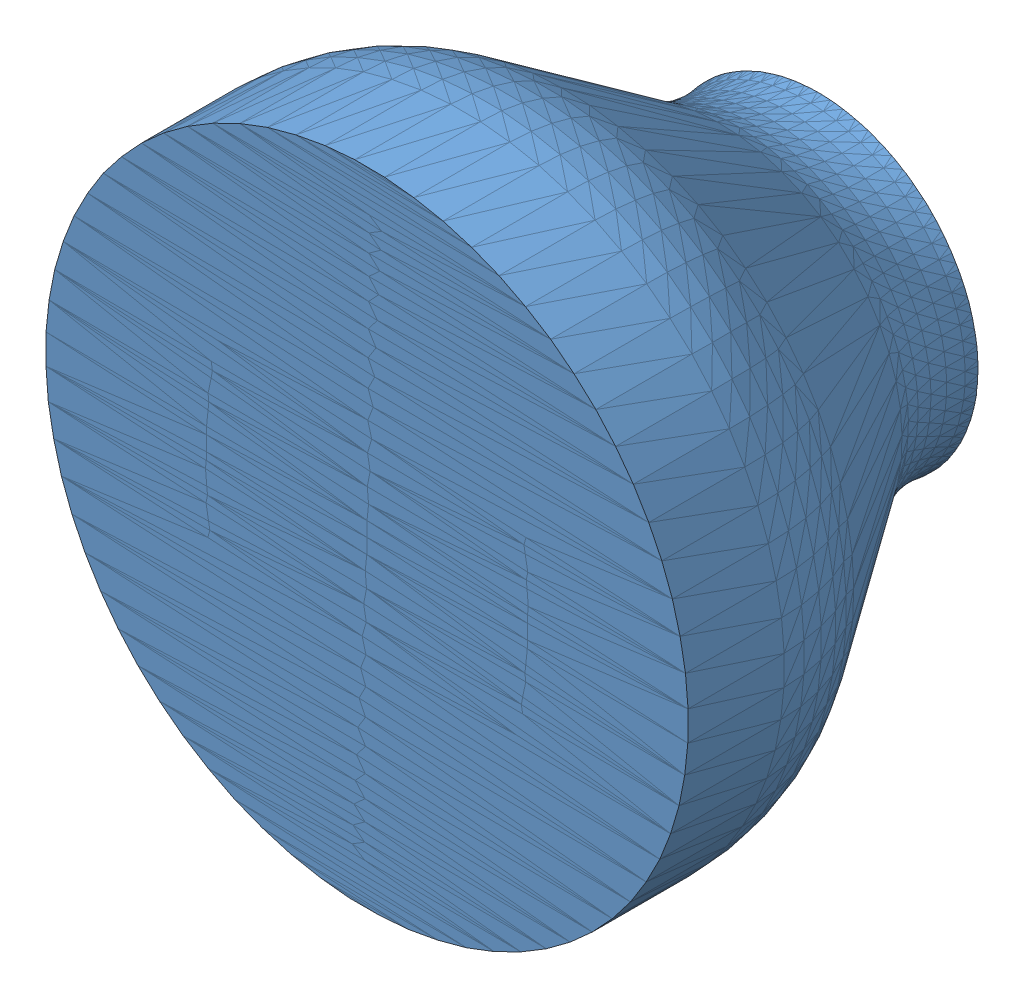
SolidWorks assembly Noyau supérieur, configuration Défaut. Lengths in mm.
Overall size (18.25 18.25 12.83).
3 component instances, 3 part files, 0 mates.
Components (placement in the parent):
- obj6-1: obj6 [Défaut] at (0 15 0) x (1 0 0) z (0 -1 0) (suppressed, hidden)
- obj7-1: obj7 [Défaut] at origin size (18.25 18.25 12.83)
- obj8-1: obj8 [Défaut] at origin (suppressed, hidden)
